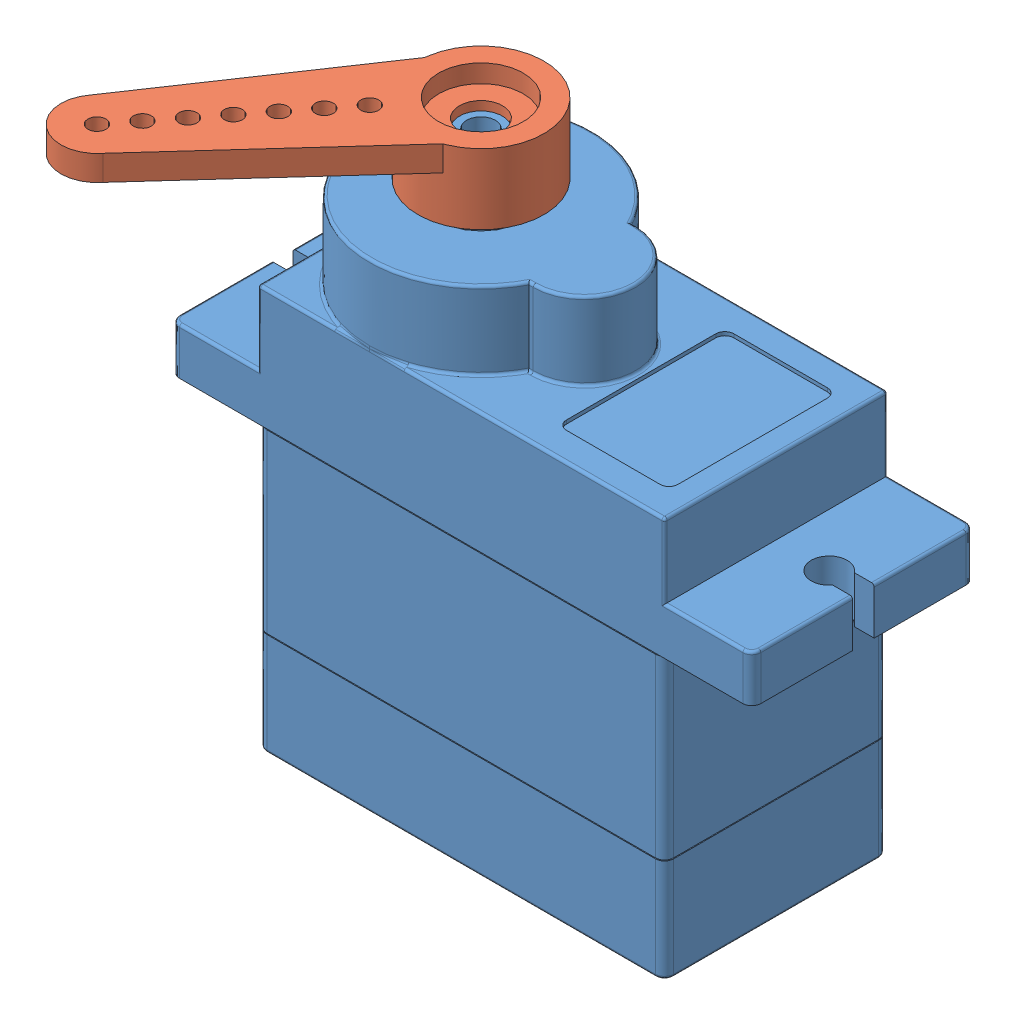
SolidWorks assembly Assem2, configuration Default. Lengths in mm.
Overall size (34.62 31.3 21.94).
2 component instances, 2 part files, 2 mates.
Components (placement in the parent):
- microservoSG90-1: microservoSG90 [Default] at (-0.2484 -13.2851 0) size (32.3 29.8 12.5)
- microservoArm-1: microservoArm [A3] at (-5.3484 18.0149 0) x (-0.6172 0 0.786806) z (0.786806 0 0.6172) size (20.7 3.9 7)
Mates (geometry in assembly coordinates):
- Concentric1: concentric: cylinder of microservoSG90-1 through (-5.3484 16.5149 0) axis (0 -1 0) radius 2.45; cylinder of microservoArm-1 through (-5.3484 14.1149 0) axis (0 1 0) radius 2.45
- Coincident1: coincident anti-aligned: plane of microservoSG90-1 through (-5.3484 16.5149 0) normal (0 1 0); plane of microservoArm-1 through (-5.3484 16.5149 0) normal (0 -1 0)
